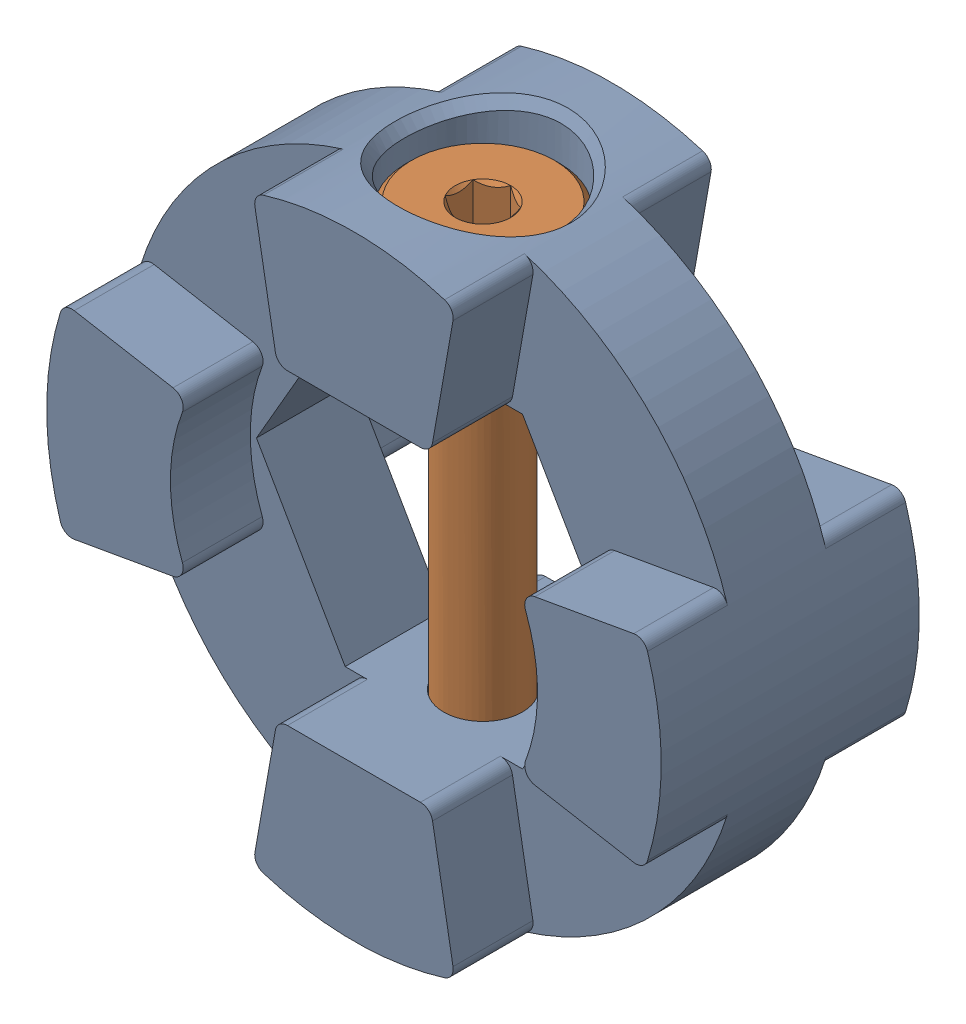
SolidWorks assembly 4 Tooth Dog Assem, configuration Default. Lengths in mm.
Overall size (25.4 25.4 10.67).
2 component instances, 2 part files, 0 mates.
Components (placement in the parent):
- 4 Tooth Dog-1: 4 Tooth Dog [Default] at (5.547 14.9514 -15.1168) size (25.4 25.4 10.67)
- .125 dia x 0.625 lg shoulder screw-1: .125 dia x 0.625 lg shoulder screw [Default] at (5.547 26.0639 -13.0848) x (1 0 0) z (0 1 0) size (6.35 6.35 23.22)
